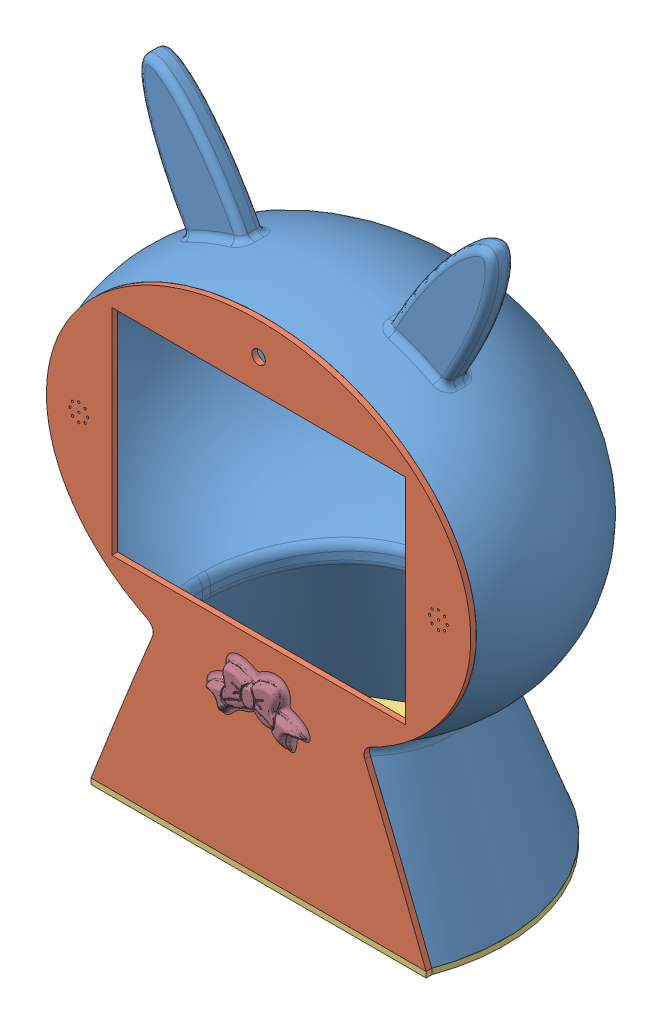
SolidWorks assembly Prototype_4-5, configuration Default. Lengths in mm.
Overall size (402 545.54 320).
4 component instances, 4 part files, 5 mates.
Components (placement in the parent):
- Main_Casing-1: Main_Casing [Default] at origin size (402 540.54 320)
- Front_Pannle-1: Front_Pannle [Default] at (0 0 54.93) size (375.8 425.3 5.02)
- Bottom-1: Bottom [Default] at (0 -280 0) x (1 0 0) z (0 1 0) size (316.36 218.11 5)
- bow-1: bow [Default] at (0 -140 59.9293) x (0 -1 0) z (0.000006 0 1) size (52.62 91.33 10)
Mates (geometry in assembly coordinates):
- Coincident1: coincident anti-aligned: plane of Main_Casing-1 through (-200 -98.1514 54.93) normal (0 0 1); plane of Front_Pannle-1 through (-121.6492 -207.0588 54.93) normal (0 0 -1)
- Coincident2: coincident anti-aligned: plane of Main_Casing-1 through (153.1818 -275 0) normal (0 -1 0); plane of Bottom-1 through (0 -275 0) normal (0 1 0)
- Coincident3: coincident aligned: line of Front_Pannle-1 through (-148.3381 -275 59.93) axis (1 0 0); line of Bottom-1 through (-148.3381 -275 59.93) axis (1 0 0)
- Coincident4: coincident aligned: circle of Main_Casing-1; circle of Bottom-1
- Coincident5: coincident anti-aligned: plane of Front_Pannle-1 through (-121.6492 -207.0588 59.93) normal (0 0 1); plane of bow-1 through (0 -140 59.93) normal (0 0 -1)
